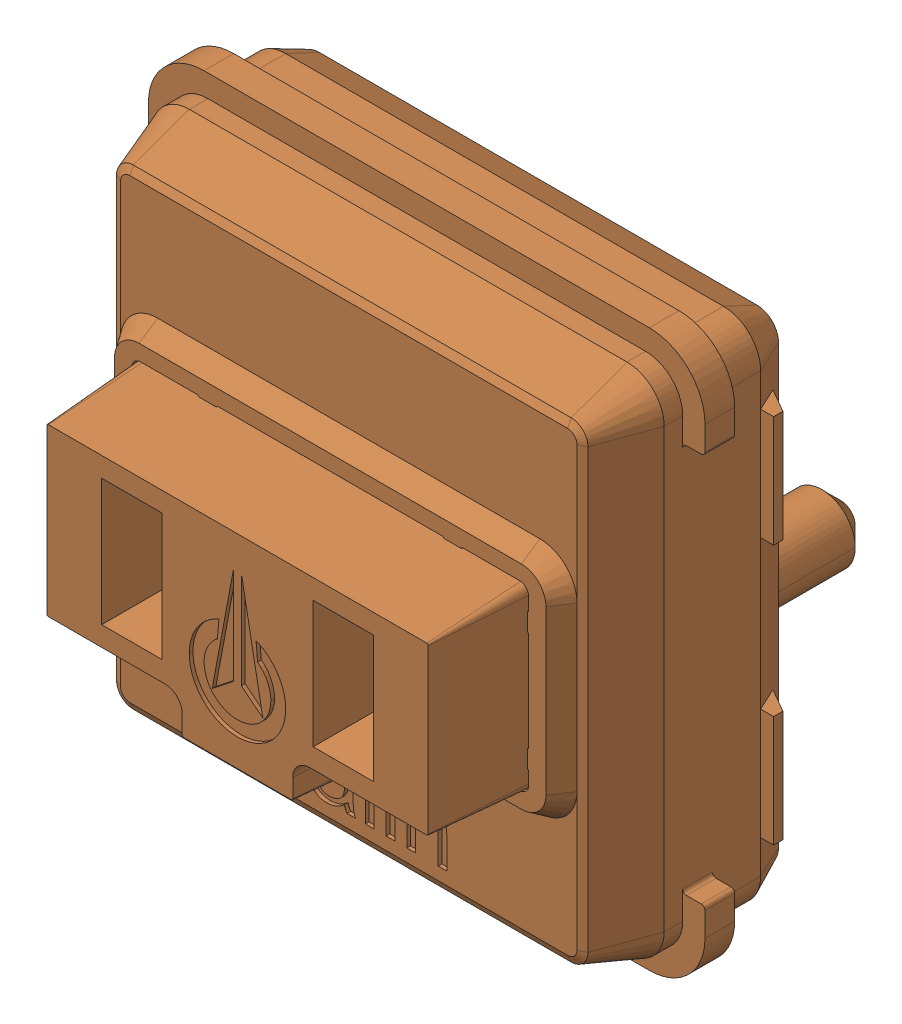
SolidWorks assembly SW8_1.step, configuration Default. Lengths in mm.
Overall size (15 15 11.1).
2 component instances, 2 part files, 0 mates.
Components (placement in the parent):
- WS2812-2020_1.step-11: WS2812-2020_1.step [Default] at (466.1066 231.0345 0.3) x (1 0 0) z (0 -1 0) size (2.2 0.86 2)
- Kailh LP Choc Burnt Orange_1.step-11: Kailh LP Choc Burnt Orange_1.step [Default] at (466 226.3933 2.7) x (0 -1 0) z (-1 0 0) size (15 11.1 15)
